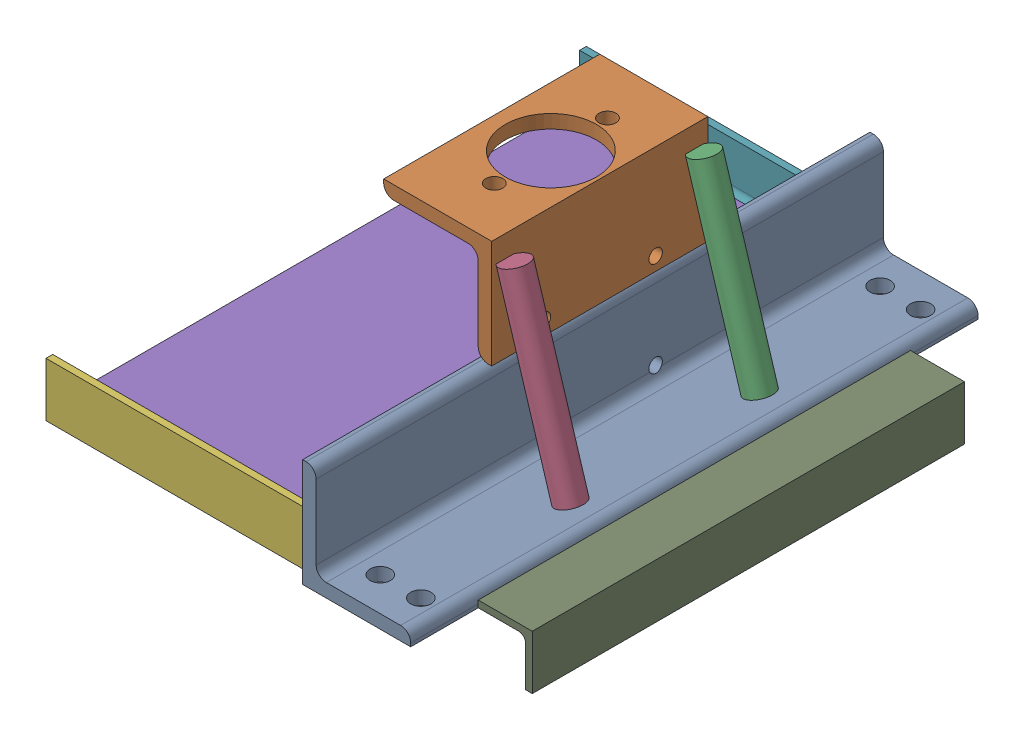
SolidWorks assembly 01-048-00-0, configuration Default. Lengths in mm.
Overall size (406.4 247.65 533.4).
9 component instances, 6 part files, 0 mates.
Components (placement in the parent):
- 01-042-00-0-1: 01-042-00-0 [Default] at origin size (101.6 101.6 533.4)
- 01-043-00-0-1: 01-043-00-0 [Default] at (12.7 203.2 0) x (-1 0 0) z (0 0 1) size (101.6 101.6 203.2)
- 01-047-00-0-1: 01-047-00-0 [Default] at (74.1068 15.97 -88.9) x (0.948496 0.291905 -0.123074) z (0.11763 0.036201 0.992397) size (25.4 177.8 25.4)
- 01-047-00-0-2: 01-047-00-0 [Default] at (74.1066 15.5263 89.0193) x (0.948496 0.291905 -0.123074) z (0.11763 0.036201 0.992397) size (25.4 177.8 25.4)
- 01-074-00-0-1: 01-074-00-0 [Default] at (0 6.35 241.3) x (0 0 -1) z (1 0 0) size (482.6 3.17 254)
- 01-105-00-0-1: 01-105-00-0 [Default] at (-127 0 254) x (0 0 -1) z (1 0 0) size (50.8 50.8 254)
- 01-105-00-0-2: 01-105-00-0 [Default] at (-127 0 -254) x (0 1 0) z (1 0 0) size (50.8 50.8 254)
- 01-106-00-0-1: 01-106-00-0 [Default] at (-254 6.35 0) x (0 -1 0) z (0 0 1) size (50.8 50.8 406.4)
- 01-106-00-0-2: 01-106-00-0 [Default] at (152.4 6.35 0) x (-1 0 0) z (0 0 1) size (50.8 50.8 406.4)
